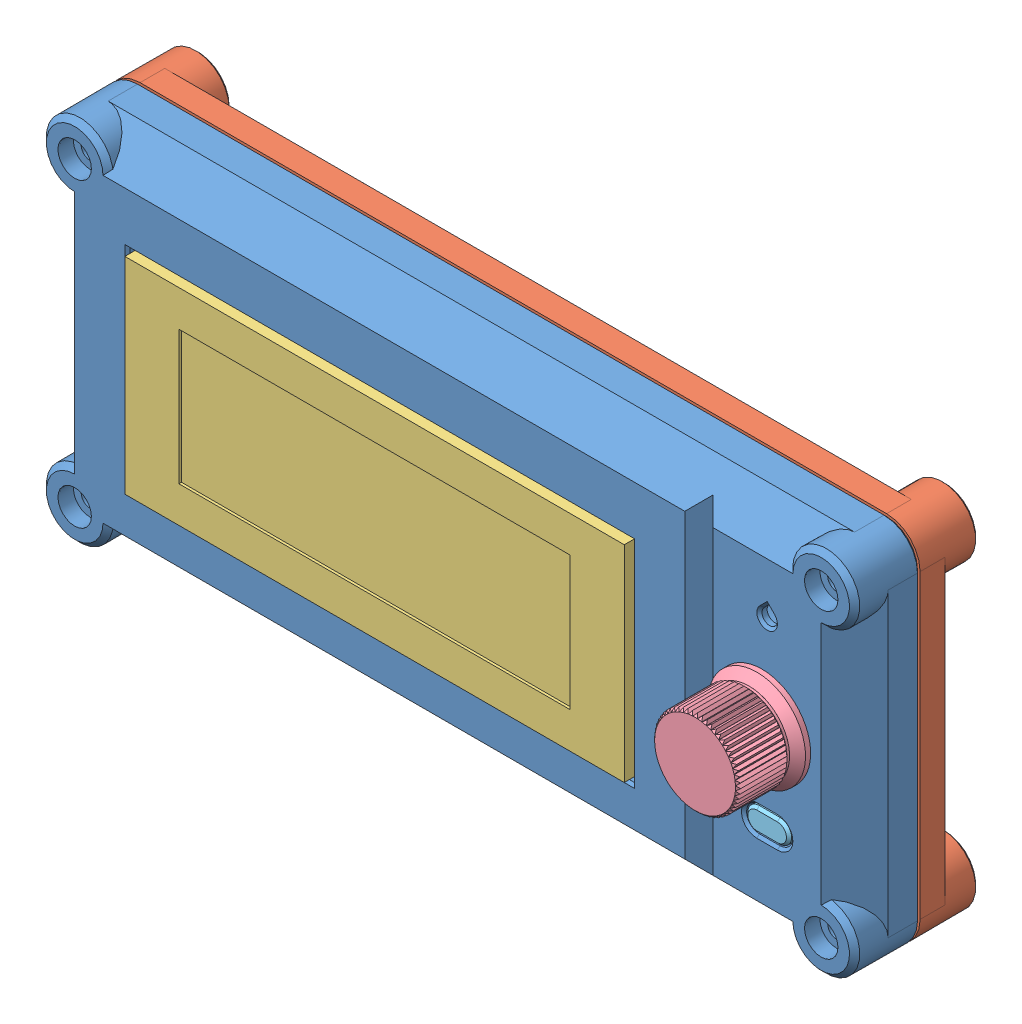
SolidWorks assembly Controller Case Assembly, configuration Default. Lengths in mm.
Overall size (158 71.5 39.7).
5 component instances, 5 part files, 14 mates.
Components (placement in the parent):
- Front Plate-1: Front Plate [Default] at origin size (158 71.5 14)
- Back Plate-1: Back Plate [Default] at origin size (158 71.5 11.3)
- Part1-1: Part1 [Default] x (1 0 0) z (0 0 -1) size (150 63.5 26.7)
- Knob (Machined)-1: Knob (Machined) [Default] at (62 -2.5 17.5) size (18.9 18.9 13)
- Button-1: Button [Default] at (62 -20 3.65) size (8.5 6 10.35)
Mates (geometry in assembly coordinates):
- Coincident1: coincident aligned: plane of Back Plate-1 through (0 0 0) normal (0 0 1); plane of assembly through (0 0 0) normal (0 0 1)
- Coincident2: coincident aligned: plane of Back Plate-1 through (0 0 0) normal (0 1 0); plane of assembly through (0 0 0) normal (0 1 0)
- Coincident3: coincident aligned: plane of Back Plate-1 through (0 0 0) normal (1 0 0); plane of assembly through (0 0 0) normal (1 0 0)
- Coincident4: coincident aligned: plane of Back Plate-1 through (0 0 0) normal (0 0 1); plane of Front Plate-1 through (0 0 0) normal (0 0 1)
- Coincident5: coincident aligned: plane of Back Plate-1 through (0 0 0) normal (0 1 0); plane of Front Plate-1 through (0 0 0) normal (0 1 0)
- Coincident6: coincident aligned: plane of Back Plate-1 through (0 0 0) normal (1 0 0); plane of Front Plate-1 through (0 0 0) normal (1 0 0)
- Coincident10: coincident anti-aligned: plane of Back Plate-1 through (0 0 0) normal (0 0 1); plane of Part1-1 through (0 0 0) normal (0 0 -1)
- Coincident11: coincident anti-aligned: plane of Back Plate-1 through (0 0 0) normal (0 1 0); plane of Part1-1 through (0 0 0) normal (0 -1 0)
- Coincident12: coincident aligned: plane of Back Plate-1 through (0 0 0) normal (1 0 0); plane of Part1-1
- Concentric1: concentric anti-aligned: cylinder of Front Plate-1 through (62 -2.5 0) axis (0 0 1) radius 4; cylinder of Knob (Machined)-1 through (62 -2.5 25.5) axis (0 0 -1) radius 3
- Distance1: distance = 1 mm anti-aligned: plane of Knob (Machined)-1 through (62 6.95 15) normal (0 0 -1); plane of Front Plate-1 through (0 0 14) normal (0 0 1)
- Width1: width anti-aligned: plane of Front Plate-1 through (64 -22.5 0) normal (0 1 0); plane of Front Plate-1 through (64 -17.5 0) normal (0 -1 0); plane of Button-1 through (60 -22.25 14) normal (0 -1 0); plane of Button-1 through (60 -17.75 14) normal (0 1 0)
- Coincident13: coincident anti-aligned: plane of Part1-1 through (62 -20 3.65) normal (0 0 1); plane of Button-1 through (60 -20 3.65) normal (0 0 -1)
- Concentric2: concentric anti-aligned: cylinder of Part1-1 through (62 -20 3.65) axis (0 0 -1) radius 1.75; line of Button-1 through (62 -20 3.65) axis (0 0 1)
